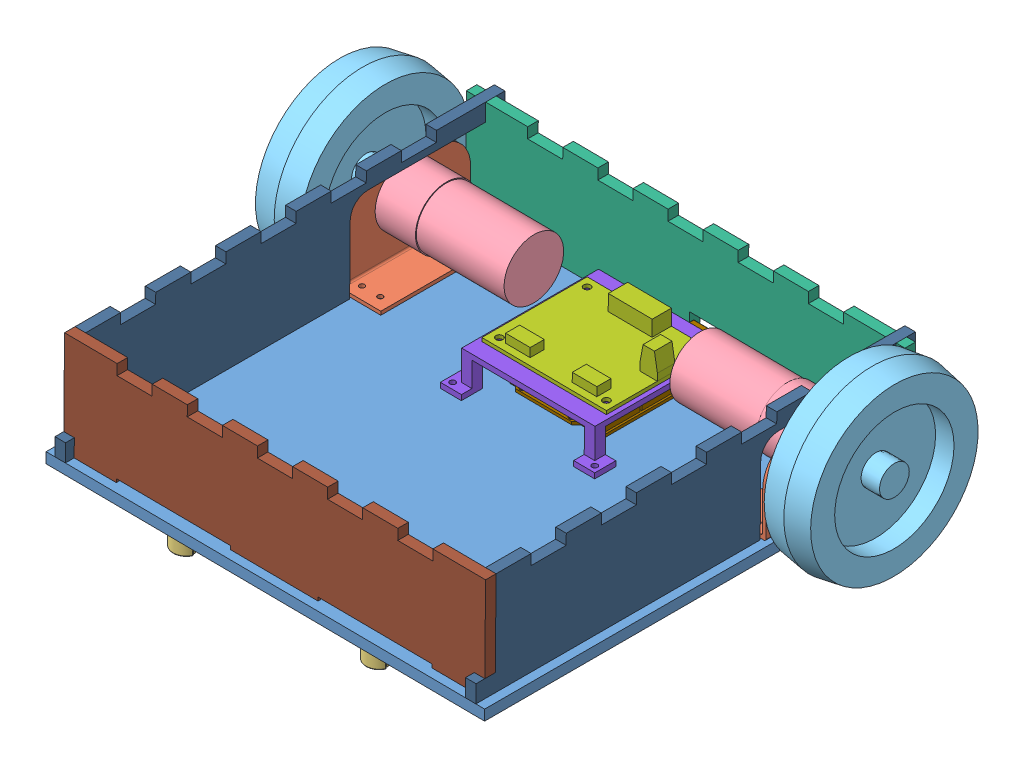
SolidWorks assembly BaseWheels, configuration Default. Lengths in mm.
Overall size (317.35 110.38 255.08).
16 component instances, 11 part files, 40 mates.
Components (placement in the parent):
- Base-1: Base [Default] at (88.9816 -302.6657 168.6836) x (0.999966 -0.008236 0.000093) z (-0.008236 -0.999966 0.000399) size (250 250 6)
- Motor Mount-1: Motor Mount [Default] at (-33.2608 -301.674 130.6722) x (0.999966 -0.008236 0.000093) z (-0.00009 0.0004 1) size (25 45 74)
- Motor Mount-2: Motor Mount [Default] at (211.2376 -303.7174 56.6951) x (-0.999966 0.008236 -0.000093) z (0.00009 -0.0004 -1) size (25 45 74)
- Ball Caster-1: Ball Caster [Default] at (143.8614 -316.1823 283.694) x (0.999966 -0.008236 0.000093) z (-0.00009 0.0004 1) size (25 13.46 15)
- Ball Caster-2: Ball Caster [Default] at (33.8651 -315.2763 283.6837) x (0.999966 -0.008236 0.000093) z (-0.00009 0.0004 1) size (25 13.46 15)
- Motor-1: Motor [Default] at (-31.0104 -271.7063 93.6604) x (0.000161 0.008235 -0.999966) z (0.999966 -0.008236 0.000093) size (35 35 85)
- Motor-2: Motor [Default] at (209.4814 -273.6872 93.6829) x (-0.000026 0.008237 0.999966) z (-0.999966 0.008236 -0.000093) size (35 35 85)
- Wheel-1: Wheel [Default] at (234.4805 -273.8931 93.6852) x (-0.000026 0.008237 0.999966) z (-0.999966 0.008236 -0.000093) size (100 100 36)
- Wheel-2: Wheel [Default] at (-56.0096 -271.5004 93.6581) x (-0.000785 -0.10656 -0.994306) z (0.999966 -0.008236 0.000093) size (100 100 36)
- Front-1: Front [Default] at (89.2107 -276.2146 48.6731) x (0.999966 -0.008236 0.000093) z (-0.00009 0.0004 1) size (250 65 6)
- MD25-1: MD25 [Default] at (53.0076 -282.3824 134.334) x (0.999966 -0.008236 0.000093) z (-0.00009 0.0004 1) size (71 16 60)
- Table-1: Table [Default] at (88.3444 -302.6862 104.3453) x (-0.00009 0.0004 1) z (-0.999966 0.008236 -0.000093) size (90 20 88)
- Arduino UNO-1: Arduino UNO [Default] at (88.3454 -302.6903 93.8836) x (-0.00009 0.0004 1) z (-0.999966 0.008236 -0.000093) size (74.8 12.1 53.3)
- Side-1: Side [Default] at (205.9395 -309.6792 43.697) x (-0.999966 0.008236 -0.000093) z (0.00009 -0.0004 -1) size (6 65 250)
- Side-2: Side [Default] at (-28.0526 -307.7519 43.6751) x (-0.999966 0.008236 -0.000093) z (0.00009 -0.0004 -1) size (6 65 250)
- Back-1: Back [Default] at (89.1893 -276.1198 285.673) x (0.999966 -0.008236 0.000093) z (-0.00009 0.0004 1) size (240 65 6)
Mates (geometry in assembly coordinates):
- Concentric1: concentric anti-aligned: circle of Motor Mount-2; circle of Base-1
- Concentric2: concentric anti-aligned: circle of Base-1; circle of Motor Mount-2
- Coincident1: coincident anti-aligned: plane of Base-1 through (88.9816 -302.6657 168.6836) normal (0.008236 0.999966 -0.000399); plane of Motor Mount-2 through (211.2376 -303.7174 56.6951) normal (-0.008236 -0.999966 0.000399)
- Concentric3: concentric aligned: circle of Base-1; circle of Motor Mount-1
- Coincident2: coincident anti-aligned: plane of Base-1 through (88.9816 -302.6657 168.6836) normal (0.008236 0.999966 -0.000399); plane of Motor Mount-1 through (-33.2608 -301.674 130.6722) normal (-0.008236 -0.999966 0.000399)
- Concentric6: concentric: circle of Base-1; circle of Ball Caster-1
- Coincident3: coincident anti-aligned: plane of Base-1 through (88.9322 -308.6655 168.686) normal (-0.008236 -0.999966 0.000399); plane of Ball Caster-1 through (143.92 -309.0725 283.6912) normal (0.008236 0.999966 -0.000399)
- Concentric7: concentric: circle of Base-1; circle of Ball Caster-2
- Coincident4: coincident anti-aligned: plane of Base-1 through (88.9322 -308.6655 168.686) normal (-0.008236 -0.999966 0.000399); plane of Ball Caster-2 through (33.9237 -308.1665 283.6809) normal (0.008236 0.999966 -0.000399)
- Coincident5: coincident anti-aligned: plane of Motor Mount-1 through (-30.8902 -256.692 130.6544) normal (0.999966 -0.008236 0.000093); plane of Motor-1 through (-31.0104 -271.7063 93.6604) normal (-0.999966 0.008236 -0.000093)
- Concentric8: concentric anti-aligned: cylinder of Motor Mount-1 through (-16.8688 -271.8228 93.6617) axis (-0.999966 0.008236 -0.000093) radius 5; cylinder of Motor-1 through (-33.0104 -271.6898 93.6602) axis (0.999966 -0.008236 0.000093) radius 5
- Coincident6: coincident anti-aligned: plane of Motor Mount-2 through (209.6083 -258.7025 56.6769) normal (-0.999966 0.008236 -0.000093); plane of Motor-2 through (209.4814 -273.6872 93.6829) normal (0.999966 -0.008236 0.000093)
- Concentric9: concentric anti-aligned: cylinder of Motor Mount-2 through (195.3397 -273.5707 93.6816) axis (0.999966 -0.008236 0.000093) radius 5; cylinder of Motor-2 through (211.4813 -273.7036 93.6831) axis (-0.999966 0.008236 -0.000093) radius 5
- Concentric10: concentric anti-aligned: cylinder of Motor-2 through (221.481 -273.786 93.684) axis (-0.999966 0.008236 -0.000093) radius 2.5; cylinder of Wheel-1 through (211.4813 -273.7036 93.6831) axis (0.999966 -0.008236 0.000093) radius 2.5
- Coincident7: coincident anti-aligned: plane of Motor-2 through (211.4813 -273.7036 93.6831) normal (0.999966 -0.008236 0.000093); plane of Wheel-1 through (211.4813 -273.7036 93.6831) normal (-0.999966 0.008236 -0.000093)
- Concentric12: concentric anti-aligned: cylinder of Motor-1 through (-43.01 -271.6075 93.6593) axis (0.999966 -0.008236 0.000093) radius 2.5; cylinder of Wheel-2 through (-33.0104 -271.6898 93.6602) axis (-0.999966 0.008236 -0.000093) radius 2.5
- Coincident8: coincident anti-aligned: plane of Motor-1 through (-33.0104 -271.6898 93.6602) normal (-0.999966 0.008236 -0.000093); plane of Wheel-2 through (-33.0104 -271.6898 93.6602) normal (0.999966 -0.008236 0.000093)
- Concentric13: concentric aligned: circle of Base-1; circle of Motor Mount-1
- Concentric14: concentric: circle of Base-1; circle of Ball Caster-1
- Concentric15: concentric: circle of Base-1; circle of Ball Caster-2
- Coincident9: coincident anti-aligned: line of Base-1 through (173.9896 -303.4138 48.6916) axis (-0.00009 0.0004 1); line of Front-1 through (173.989 -303.4114 54.6916) axis (0.00009 -0.0004 -1)
- Coincident10: coincident anti-aligned: line of Base-1 through (3.9953 -302.0136 48.6757) axis (-0.00009 0.0004 1); line of Front-1 through (3.9948 -302.0112 54.6757) axis (0.00009 -0.0004 -1)
- Coincident11: coincident anti-aligned: plane of Base-1 through (89.4722 -244.4038 54.6604) normal (0.00009 -0.0004 -1); plane of Front-1 through (89.2102 -276.2122 54.6731) normal (-0.00009 0.0004 1)
- Coincident13: coincident anti-aligned: plane of Base-1 through (88.9816 -302.6657 168.6836) normal (0.008236 0.999966 -0.000399); plane of Table-1 through (88.3444 -302.6862 104.3453) normal (-0.008236 -0.999966 0.000399)
- Coincident18: coincident anti-aligned: plane of MD25-1 through (53.0076 -282.3824 134.334) normal (-0.008236 -0.999966 0.000399); plane of Table-1 through (88.5091 -282.6868 104.3373) normal (0.008236 0.999966 -0.000399)
- Concentric16: concentric anti-aligned: circle of MD25-1; circle of Table-1
- Coincident19: coincident anti-aligned: plane of Base-1 through (88.9816 -302.6657 168.6836) normal (0.008236 0.999966 -0.000399); plane of Arduino UNO-1 through (114.9915 -302.8966 126.8861) normal (-0.008236 -0.999966 0.000399)
- Coincident20: coincident anti-aligned: plane of Front-1 through (89.2102 -276.2122 54.6731) normal (-0.00009 0.0004 1); plane of Arduino UNO-1 through (106.098 -290.7518 54.6804) normal (0.00009 -0.0004 -1)
- Coincident21: coincident anti-aligned: plane of Base-1 through (89.4641 -244.3682 143.6603) normal (-0.00009 0.0004 1); plane of Side-2 through (30.2628 -308.1923 143.6805) normal (0.00009 -0.0004 -1)
- Coincident22: coincident anti-aligned: plane of Base-1 through (-30.5341 -243.3698 168.6491) normal (0.999966 -0.008236 0.000093); plane of Side-2 through (-31.0525 -307.7272 43.6748) normal (-0.999966 0.008236 -0.000093)
- Coincident23: coincident anti-aligned: plane of Base-1 through (88.9816 -302.6657 168.6836) normal (0.008236 0.999966 -0.000399); plane of Side-2 through (30.3212 -302.2325 43.6782) normal (-0.008236 -0.999966 0.000399)
- Coincident24: coincident anti-aligned: plane of Base-1 through (203.458 -245.2971 168.671) normal (0.999966 -0.008236 0.000093); plane of Side-1 through (202.9396 -309.6545 43.6967) normal (-0.999966 0.008236 -0.000093)
- Coincident25: coincident anti-aligned: plane of Base-1 through (89.4641 -244.3682 143.6603) normal (-0.00009 0.0004 1); plane of Side-1 through (264.2548 -310.1196 143.7024) normal (0.00009 -0.0004 -1)
- Coincident26: coincident anti-aligned: plane of Base-1 through (88.9816 -302.6657 168.6836) normal (0.008236 0.999966 -0.000399); plane of Side-1 through (264.3133 -304.1598 43.7) normal (-0.008236 -0.999966 0.000399)
- Coincident27: coincident anti-aligned: plane of Side-2 through (30.4036 -292.2328 43.6742) normal (0.008236 0.999966 -0.000399); plane of Back-1 through (-30.9363 -291.6583 217.178) normal (-0.008236 -0.999966 0.000399)
- Coincident28: coincident anti-aligned: plane of Side-2 through (-25.0527 -307.7766 43.6754) normal (0.999966 -0.008236 0.000093); plane of Back-1 through (-25.0683 -307.7072 217.1849) normal (-0.999966 0.008236 -0.000093)
- Coincident29: coincident aligned: plane of Base-1 through (88.9322 -308.6655 168.686) normal (-0.008236 -0.999966 0.000399); plane of Back-1 through (-31.0746 -307.6291 288.6748) normal (-0.008236 -0.999966 0.000399)
- Coincident30: coincident anti-aligned: plane of Base-1 through (89.4516 -244.3126 282.6603) normal (-0.00009 0.0004 1); plane of Back-1 through (89.1896 -276.121 282.673) normal (0.00009 -0.0004 -1)
- Concentric17: concentric aligned: cylinder of MD25-1 through (58.0124 -282.4466 79.3345) axis (0.008236 0.999966 -0.000399) radius 2; cylinder of Table-1 through (57.8477 -302.446 79.3425) axis (0.008236 0.999966 -0.000399) radius 2.1
- Coincident31: coincident aligned: plane of Table-1 through (88.3444 -302.6862 104.3453) normal (-0.999966 0.008236 -0.000093); plane of Arduino UNO-1 through (88.3454 -302.6903 93.8836) normal (-0.999966 0.008236 -0.000093)
